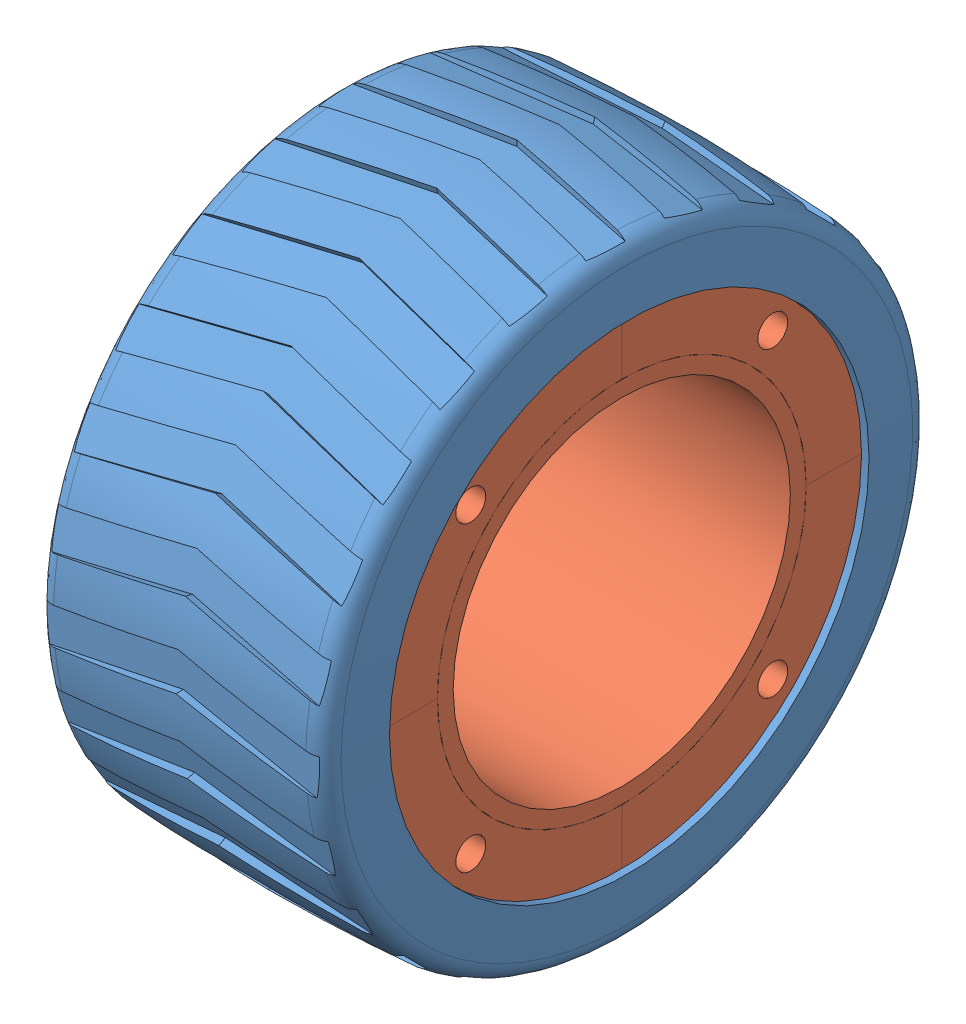
SolidWorks assembly Reifen-Vorne-Gussform, configuration Standard. Lengths in mm.
Overall size (37 70 70).
6 component instances, 2 part files, 9 mates.
Components (placement in the parent):
- Reifen-Vorne-1: Reifen-Vorne [Standard] at origin size (39 83.29 83.29) (hidden)
- Reifen-Vorne-Gussform-1: Reifen-Vorne-Gussform [Innen] at origin size (37 60 60)
- Reifen-Vorne-Gussform-2: Reifen-Vorne-Gussform [Außen] at origin size (37 35 35)
- Reifen-Vorne-Gussform-3: Reifen-Vorne-Gussform [Außen] x (1 0 0) z (0 -1 0) size (37 35 35)
- Reifen-Vorne-Gussform-4: Reifen-Vorne-Gussform [Außen] x (1 0 0) z (0 0 -1) size (37 35 35)
- Reifen-Vorne-Gussform-5: Reifen-Vorne-Gussform [Außen] x (1 0 0) z (0 1 0) size (37 35 35)
Mates (geometry in assembly coordinates):
- Deckungsgleich1: coincident aligned: plane of Reifen-Vorne-1 through (0 0 0) normal (1 0 0); plane of assembly through (0 0 0) normal (1 0 0)
- Deckungsgleich2: coincident aligned: plane of Reifen-Vorne-1 through (0 0 0) normal (0 1 0); plane of assembly through (0 0 0) normal (0 1 0)
- Deckungsgleich3: coincident aligned: plane of Reifen-Vorne-1 through (0 0 0) normal (0 0 1); plane of assembly through (0 0 0) normal (0 0 1)
- Deckungsgleich4: coincident aligned: plane of Reifen-Vorne-Gussform-1 through (0 0 0) normal (0 0 1); plane of assembly through (0 0 0) normal (0 0 1)
- Deckungsgleich5: coincident aligned: plane of Reifen-Vorne-Gussform-1 through (0 0 0) normal (0 1 0); plane of assembly through (0 0 0) normal (0 1 0)
- Deckungsgleich6: coincident aligned: plane of Reifen-Vorne-Gussform-1 through (0 0 0) normal (1 0 0); plane of assembly through (0 0 0) normal (1 0 0)
- Deckungsgleich7: coincident aligned: plane of Reifen-Vorne-Gussform-2 through (0 0 0) normal (1 0 0); plane of assembly through (0 0 0) normal (1 0 0)
- Deckungsgleich8: coincident aligned: plane of Reifen-Vorne-Gussform-2 through (0 0 0) normal (0 1 0); plane of assembly through (0 0 0) normal (0 1 0)
- Deckungsgleich9: coincident aligned: plane of Reifen-Vorne-Gussform-2 through (0 0 0) normal (0 0 1); plane of assembly through (0 0 0) normal (0 0 1)
